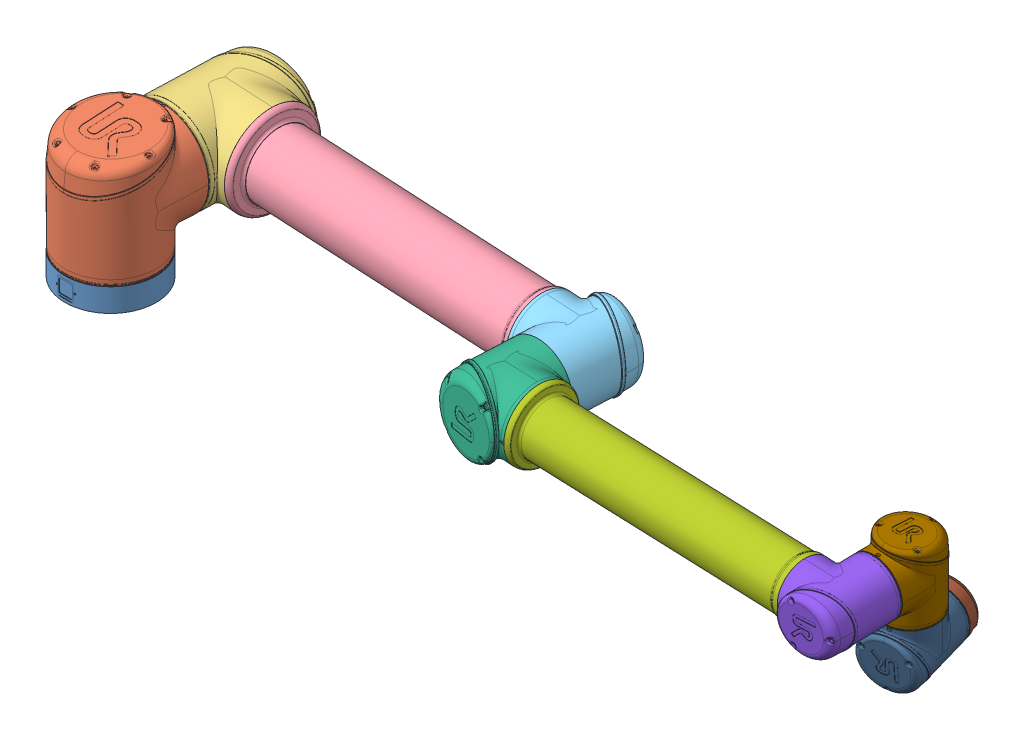
SolidWorks assembly UR10_movable, configuration Default. Lengths in mm.
Overall size (1341.91 293.2 372.89).
11 component instances, 11 part files, 20 mates.
Components (placement in the parent):
- Base-1: Base [Default] at (2.4075 117.976 104.3538) size (150 38 150)
- Motor1-1: Motor1 [Default] at (2.4075 117.976 104.3538) x (0.999496 0 0.031732) z (-0.031732 0 0.999496) size (163.23 199.46 221.51)
- Motor2-1: Motor2 [Default] at (-125.4992 248.698 100.2931) x (-0.021255 -0.999774 -0.000675) z (-0.031732 0 0.999496) size (162.4 221.51 199.46)
- Link1-1: Link1 [Default] at (-125.0515 259.8249 99.9546) x (-0.02322 -0.997771 0.062554) z (-0.030324 0.063245 0.997537) size (150 460.6 150)
- Motor3-1: Motor3 [Default] at (-124.6385 251.4599 100.2995) x (-0.021646 -0.999697 0.011695) z (-0.031466 0.012373 0.999428) size (122.2 127.99 142.04)
- Motor4-1: Motor4 [Default] at (-125.4084 239.9632 100.4176) x (-0.006926 -0.999902 0.012161) z (-0.031466 0.012373 0.999428) size (122.2 127.38 132.89)
- Link2-1: Link2 [Default] at (-125.3538 246.0748 99.9536) x (-0.010864 -0.990244 0.138922) z (-0.030333 0.139193 0.989801) size (116 451.3 116)
- Motor5-1: Motor5 [Default] at (-125.4271 236.8029 100.3524) x (-0.004848 -0.998562 -0.053388) z (-0.031853 -0.053208 0.998075) size (98 194.56 134.84)
- Motor6-1: Motor6 [Default] at (1261.4817 1536.3725 213.8946) x (-0.997845 0.059013 -0.028699) z (-0.031853 -0.053208 0.998075) size (98 134.84 194.56)
- Motor7-1: Motor7 [Default] at (1304.6651 1534.1363 209.3757) x (-0.971109 0.042947 0.234739) z (0.231636 -0.066852 0.970503) size (98 194.56 134.84)
- Bracket-1: Bracket [Default] at (237.4688 1098.8227 434.1041) x (-0.68578 -0.718799 0.114166) z (0.231636 -0.066852 0.970503) size (90 90.13 30.68)
Mates (geometry in assembly coordinates):
- Concentric1: concentric aligned: cylinder of Base-1 through (2.4075 117.976 104.3538) axis (0 1 0) radius 75; cylinder of Motor1-1 through (2.4075 327.9789 104.3538) axis (0 1 0) radius 75.01
- Coincident1: coincident anti-aligned: plane of Base-1 through (-50.6256 155.976 51.3208) normal (0 1 0); plane of Motor1-1 through (4.781 155.976 29.5915) normal (0 -1 0)
- Coincident2: coincident anti-aligned: plane of Motor1-1 through (79.0991 245.976 20.7453) normal (0.031732 0 -0.999496); plane of Motor2-1 through (79.8818 244.3853 20.7702) normal (-0.031732 0 0.999496)
- Concentric2: concentric anti-aligned: circle of Motor1-1; circle of Motor2-1
- Concentric3: concentric anti-aligned: circle of Motor2-1; circle of Link1-1
- Coincident3: coincident anti-aligned: plane of Motor2-1 through (95.5024 318.1304 -68.7793) normal (0.99927 -0.021266 0.031725); plane of Link1-1 through (96.2038 239.4037 -143.6445) normal (-0.99927 0.021266 -0.031725)
- Coincident4: coincident anti-aligned: plane of Link1-1 through (555.9522 230.6839 -112.0735) normal (0.99927 -0.021266 0.031725); plane of Motor3-1 through (554.1934 234.3521 -54.2168) normal (-0.99927 0.021266 -0.031725)
- Concentric4: concentric aligned: circle of Link1-1; circle of Motor3-1
- Concentric5: concentric anti-aligned: cylinder of Motor3-1 through (618.3148 233.7798 15.5478) axis (-0.031466 0.012373 0.999428) radius 58; cylinder of Motor4-1 through (622.4238 232.1641 -114.9602) axis (0.031466 -0.012373 -0.999428) radius 58
- Coincident5: coincident anti-aligned: plane of Motor3-1 through (618.3019 233.7849 15.9569) normal (-0.031466 0.012373 0.999428); plane of Motor4-1 through (618.3019 233.7849 15.9569) normal (0.031466 -0.012373 -0.999428)
- Concentric6: concentric aligned: circle of Motor4-1; circle of Link2-1
- Coincident6: coincident anti-aligned: plane of Motor4-1 through (682.689 234.09 77.7144) normal (0.999481 -0.006539 0.031549); plane of Link2-1 through (683.3191 291.5241 69.6569) normal (-0.999481 0.006539 -0.031549)
- Concentric7: concentric aligned: circle of Link2-1; circle of Motor5-1
- Coincident7: coincident anti-aligned: plane of Link2-1 through (1134.2435 275.7006 85.7009) normal (0.999481 -0.006539 0.031549); plane of Motor5-1 through (1133.968 275.0757 94.3015) normal (-0.999481 0.006539 -0.031549)
- Coincident8: coincident anti-aligned: plane of Motor5-1 through (1234.4327 233.776 33.4871) normal (0.031853 0.053208 -0.998075); plane of Motor6-1 through (1145.7868 236.6653 30.8121) normal (-0.031853 -0.053208 0.998075)
- Concentric8: concentric aligned: circle of Motor5-1; circle of Motor6-1
- Coincident9: coincident anti-aligned: plane of Motor6-1 through (1189.2979 177.8188 -69.8909) normal (-0.057373 -0.996838 -0.054973); plane of Motor7-1 through (1230.6009 173.5474 -35.5415) normal (0.057373 0.996838 0.054973)
- Concentric9: concentric aligned: circle of Motor6-1; circle of Motor7-1
- Concentric10: concentric anti-aligned: cylinder of Motor7-1 through (1184.774 121.6078 -28.1815) axis (-0.231636 0.066852 -0.970503) radius 45; cylinder of Bracket-1 through (1163.4171 127.7715 -117.6619) axis (0.231636 -0.066852 0.970503) radius 45
- Coincident10: coincident anti-aligned: plane of Motor7-1 through (1167.9138 81.1101 -90.5224) normal (-0.231636 0.066852 -0.970503); plane of Bracket-1 through (1201.3421 158.0785 -93.199) normal (0.231636 -0.066852 0.970503)
